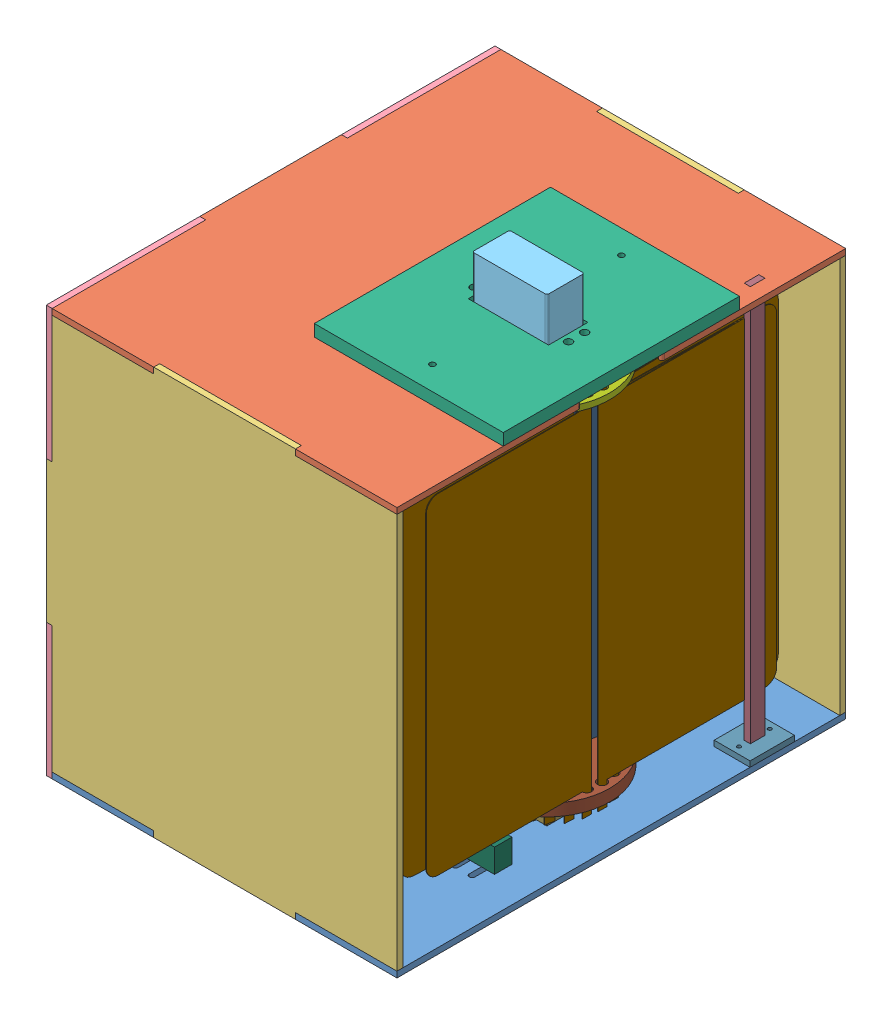
SolidWorks assembly BasicFlipbook, configuration Default. Lengths in mm.
Overall size (189.19 247.83 241.3).
43 component instances, 15 part files, 34 mates.
Components (placement in the parent):
- sidePanel-bearing-1: sidePanel-bearing [Default] at (77.8088 -538.0926 524.9276) size (188.59 3.17 241.3)
- sidePanel-spindle-1: sidePanel-spindle [Default] at (77.8088 -322.1926 524.9276) size (188.59 3.17 241.3)
- topPanel-1: topPanel [Default] at (170.5188 -428.5551 283.6276) x (0 -1 0) z (0 0 1) size (219.07 188.59 3.17)
- topPanel-2: topPanel [Default] at (170.5188 -428.5551 521.7526) x (0 -1 0) z (0 0 1) size (219.07 188.59 3.17)
- backPanel-1: backPanel [Default] at (77.8088 -538.0926 524.9276) x (0 1 0) z (0 0 1) size (219.07 3.17 241.3)
- servo-1: servo [Default] at (213.1908 -290.2676 404.2776) x (1 0 0) z (0 -1 0) size (52.83 20.07 43.1)
- sidePanel-motor-1: sidePanel-motor [Default] at (77.8088 -319.0176 524.9276) size (101.6 6.35 127)
- FlipHubAssy_11_14_16-2: FlipHubAssy_11_14_16 [Default] at (223.2238 -424.2676 404.2776) x (0 1 0) z (0.343761 0 0.939057) size (212.25 171.9 216.35) (flexible)
  - Hub_11_16_16v1-3: Hub_11_16_16v1 [Kerf Removed] at (92.075 0 0) x (0 -0.836215 0.548402) z (1 0 0) size (67.6 67.6 3.17)
  - 4mmShaft-1: 4mmShaft [Default] at (-110.65 0 0) x (0 0.397838 0.917456) z (1 0 0) size (4 4 201.85)
  - flipcard-2: flipcard [Default] at (101.6 -15.2897 -21.654) x (-1 0 0) z (0 0.118273 0.992981) size (203.2 0.36 88.9)
  - flipcard-3: flipcard [Default] at (101.6 -20.7049 -16.8264) x (-1 0 0) z (0 0.229727 0.973255) size (203.2 0.36 88.9)
  - flipcard-4: flipcard [Default] at (101.6 -24.7798 -10.679) x (-1 0 0) z (0 0.290896 0.956755) size (203.2 0.36 88.9)
  - flipcard-5: flipcard [Default] at (101.6 -27.1726 -3.6323) x (-1 0 0) z (0 0.324243 0.945974) size (203.2 0.36 88.9)
  - flipcard-6: flipcard [Default] at (101.6 -27.6554 3.8125) x (-1 0 0) z (0 0.355007 0.934864) size (203.2 0.36 88.9)
  - flipcard-7: flipcard [Default] at (101.6 6.9617 25.991) x (-1 0 0) z (0 -0.804275 -0.594258) size (203.2 0.36 88.9)
  - flipcard-8: flipcard [Default] at (101.6 13.6608 22.8217) x (-1 0 0) z (0 -0.829103 -0.559096) size (203.2 0.36 88.9)
  - flipcard-9: flipcard [Default] at (101.6 12.4258 -23.2935) x (-1 0 0) z (0 -0.27854 0.960425) size (203.2 0.36 88.9)
  - flipcard-10: flipcard [Default] at (101.6 19.1668 18.301) x (-1 0 0) z (0 -0.912348 -0.409415) size (203.2 0.36 88.9)
  - flipcard-11: flipcard [Default] at (101.6 25.8239 6.5692) x (-1 0 0) z (0 -0.973268 0.229671) size (203.2 0.36 88.9)
  - flipcard-12: flipcard [Default] at (101.6 -7.402 26.2839) x (-1 0 0) z (0 -0.588891 -0.808212) size (203.2 0.36 88.9)
  - flipcard-13: flipcard [Default] at (101.6 23.2571 13.1974) x (-1 0 0) z (0 -0.999195 0.040112) size (203.2 0.36 88.9)
  - flipcard-14: flipcard [Default] at (101.6 -0.029 26.9321) x (-1 0 0) z (0 -0.634806 -0.772672) size (203.2 0.36 88.9)
  - flipcard-15: flipcard [Default] at (101.6 -14.3329 23.6973) x (-1 0 0) z (0 -0.524162 -0.851618) size (203.2 0.36 88.9)
  - flipcard-16: flipcard [Default] at (101.6 25.5857 -7.2828) x (-1 0 0) z (0 -0.75236 0.658752) size (203.2 0.36 88.9)
  - flipcard-17: flipcard [Default] at (101.6 -20.2143 19.2851) x (-1 0 0) z (0 -0.387069 -0.922051) size (203.2 0.36 88.9)
  - flipcard-18: flipcard [Default] at (101.6 -26.2822 11.1902) x (-1 0 0) z (0 0.343761 0.939057) size (203.2 0.36 88.9)
  - flipcard-19: flipcard [Default] at (101.6 26.6468 -0.3343) x (-1 0 0) z (0 -0.879712 0.475507) size (203.2 0.36 88.9)
  - flipcard-20: flipcard [Default] at (101.6 -25.0081 13.5575) x (-1 0 0) z (0 -0.343761 -0.939057) size (203.2 0.36 88.9)
  - flipcard-21: flipcard [Default] at (101.6 22.7931 -13.6775) x (-1 0 0) z (0 -0.570443 0.821337) size (203.2 0.36 88.9)
  - flipcard-22: flipcard [Default] at (101.6 5.6236 -25.7226) x (-1 0 0) z (0 -0.165302 0.986243) size (203.2 0.36 88.9)
  - flipcard-23: flipcard [Default] at (101.6 -1.5593 -26.2681) x (-1 0 0) z (0 -0.043757 0.999042) size (203.2 0.36 88.9)
  - flipcard-24: flipcard [Default] at (101.6 18.5239 -19.098) x (-1 0 0) z (0 -0.319136 0.947709) size (203.2 0.36 88.9)
  - flipcard-26: flipcard [Default] at (101.6 -8.628 -24.8962) x (-1 0 0) z (0 0.08016 0.996782) size (203.2 0.36 88.9)
  - CenterSupport-2: CenterSupport [After Cut Kerf Removed] at (0 3.7916 3.0025) x (1 0 0) z (0 -0.836215 0.548402) size (190.5 19.05 3.05)
  - CenterSupport-3: CenterSupport [After Cut Kerf Removed] at (0 -3.0025 3.7916) x (1 0 0) z (0 -0.548402 -0.836215) size (190.5 19.05 3.05)
  - CenterSupport-4: CenterSupport [After Cut Kerf Removed] at (0 -3.7916 -3.0025) x (1 0 0) z (0 0.836215 -0.548402) size (190.5 19.05 3.05)
  - CenterSupport-5: CenterSupport [After Cut Kerf Removed] at (0 3.0025 -3.7916) x (1 0 0) z (0 0.548402 0.836215) size (190.5 19.05 3.05)
  - Hub_11_16_16v1-thicker-3: Hub_11_16_16v1-thicker [Kerf Removed] at (-95.25 0 0) x (0 -0.548402 -0.836215) z (1 0 0) size (67.6 72.68 6.35)
  - bearingSleeve-nut-1: bearingSleeve-nut [Default] at (-109.05 0 0) x (0 -0.939057 0.343761) z (-1 0 0) size (25.4 25.4 6.95)
- stopper-2: stopper [Default] at (255.3548 -538.0926 327.0616) x (0 1 0) z (-1 0 0) size (219.07 7.87 3.3)
- stopperSupport-1: stopperSupport [Default] at (243.9268 -531.9176 311.1876) x (1 0 0) z (0 -1 0) size (19.3 23.87 3)
- switchSupport-1: switchSupport [Default] at (224.5478 -534.9176 453.6616) x (1 0 0) z (0 1 0) size (19.84 9.4 12.7)
Mates (geometry in assembly coordinates):
- Coincident49: coincident anti-aligned: plane of servo-1 through (213.1908 -319.0176 404.2776) normal (0 1 0); plane of sidePanel-motor-1 through (77.8088 -319.0176 524.9276) normal (0 -1 0)
- Parallel2: parallel anti-aligned: plane of servo-1 through (193.1248 -328.3676 394.2446) normal (0 0 -1); plane of sidePanel-motor-1 through (191.4738 -319.0176 393.7048) normal (0 0 1)
- Coincident70: coincident anti-aligned: plane of sidePanel-spindle-1 through (77.8088 -319.0176 524.9276) normal (0 1 0); plane of sidePanel-motor-1 through (77.8088 -319.0176 524.9276) normal (0 -1 0)
- Coincident87: coincident aligned: plane of sidePanel-bearing-1 through (263.2288 -534.9176 524.9276) normal (1 0 0); plane of topPanel-1 through (263.2288 -322.1926 286.8026) normal (1 0 0)
- Coincident89: coincident aligned: plane of sidePanel-bearing-1 through (263.2288 -534.9176 524.9276) normal (1 0 0); plane of topPanel-1 through (263.2288 -322.1926 286.8026) normal (1 0 0)
- Coincident90: coincident anti-aligned: plane of sidePanel-bearing-1 through (77.8088 -534.9176 524.9276) normal (0 1 0); plane of topPanel-1 through (263.2288 -534.9176 286.8026) normal (0 -1 0)
- Coincident93: coincident anti-aligned: plane of sidePanel-bearing-1 through (77.8088 -534.9176 524.9276) normal (0 1 0); plane of topPanel-2 through (263.2288 -534.9176 524.9276) normal (0 -1 0)
- Coincident94: coincident aligned: plane of sidePanel-bearing-1 through (77.8088 -534.9176 524.9276) normal (0 0 1); plane of topPanel-2 through (170.5188 -428.5551 524.9276) normal (0 0 1)
- Coincident95: coincident aligned: plane of sidePanel-bearing-1 through (77.8088 -534.9176 524.9276) normal (-1 0 0); plane of topPanel-2 through (77.8088 -322.1926 524.9276) normal (-1 0 0)
- Coincident96: coincident anti-aligned: plane of sidePanel-spindle-1 through (77.8088 -322.1926 524.9276) normal (0 -1 0); plane of topPanel-1 through (263.2288 -322.1926 286.8026) normal (0 1 0)
- Coincident97: coincident aligned: plane of sidePanel-spindle-1 through (77.8088 -319.0176 283.6276) normal (0 0 -1); plane of topPanel-1 through (170.5188 -428.5551 283.6276) normal (0 0 -1)
- Coincident98: coincident aligned: plane of sidePanel-spindle-1 through (77.8088 -319.0176 524.9276) normal (-1 0 0); plane of topPanel-1 through (77.8088 -322.1926 286.8026) normal (-1 0 0)
- Coincident99: coincident anti-aligned: plane of topPanel-1 through (77.8088 -322.1926 286.8026) normal (-1 0 0); plane of backPanel-1 through (77.8088 -538.0926 524.9276) normal (1 0 0)
- Coincident100: coincident aligned: plane of sidePanel-bearing-1 through (77.8088 -538.0926 524.9276) normal (0 -1 0); plane of backPanel-1 through (74.6338 -538.0926 524.9276) normal (0 -1 0)
- Concentric23: concentric anti-aligned: cylinder of sidePanel-spindle-1 through (223.2238 -322.1926 404.2776) axis (0 1 0) radius 43.815; cylinder of FlipHubAssy_11_14_16-2/Hub_11_16_16v1-3 through (223.2238 -329.0176 404.2776) axis (0 -1 0) radius 33.8
- Concentric24: concentric anti-aligned: cylinder of sidePanel-bearing-1 through (231.1471 -538.0926 396.3543) axis (0 1 0) radius 1.0922; cylinder of FlipHubAssy_11_14_16-2/bearingSleeve-nut-1 through (231.1471 -527.9676 396.3543) axis (0 -1 0) radius 1.0922
- Concentric25: concentric anti-aligned: cylinder of sidePanel-bearing-1 through (215.3004 -538.0926 412.2009) axis (0 1 0) radius 1.0922; cylinder of FlipHubAssy_11_14_16-2/bearingSleeve-nut-1 through (215.3004 -527.9676 412.2009) axis (0 -1 0) radius 1.0922
- Parallel4: parallel aligned: line of sidePanel-bearing-1 through (263.2288 -534.9176 524.9276) axis (0 0 -1); line of FlipHubAssy_11_14_16-2/flipcard-18 through (252.1066 -513.1676 397.776) axis (0 0 -1)
- Parallel5: parallel anti-aligned: line of sidePanel-bearing-1 through (263.2288 -538.0926 524.9276) axis (0 0 -1); line of FlipHubAssy_11_14_16-2/flipcard-20 through (251.3683 -513.1676 416.387) axis (0 0 1)
- Coincident104: coincident aligned: plane of sidePanel-bearing-1 through (77.8088 -538.0926 524.9276) normal (0 -1 0); plane of stopper-2 through (252.0528 -538.0926 327.0616) normal (0 -1 0)
- Coincident105: coincident anti-aligned: plane of sidePanel-bearing-1 through (252.0528 -534.9176 327.0616) normal (0 0 -1); plane of stopper-2 through (252.0528 -538.0926 327.0616) normal (0 0 1)
- Coincident106: coincident anti-aligned: plane of sidePanel-bearing-1 through (255.3548 -534.9176 319.1876) normal (-1 0 0); plane of stopper-2 through (255.3548 -538.0926 327.0616) normal (1 0 0)
- Coincident107: coincident aligned: plane of sidePanel-bearing-1 through (263.2288 -534.9176 524.9276) normal (1 0 0); plane of stopperSupport-1 through (263.2288 -534.9176 335.0616) normal (1 0 0)
- Coincident108: coincident anti-aligned: plane of sidePanel-bearing-1 through (77.8088 -534.9176 524.9276) normal (0 1 0); plane of stopperSupport-1 through (243.9268 -534.9176 311.1876) normal (0 -1 0)
- Coincident109: coincident anti-aligned: plane of stopper-2 through (252.0528 -538.0926 319.1876) normal (0 0 -1); plane of stopperSupport-1 through (251.9268 -534.9176 319.1876) normal (0 0 1)
- Concentric30: concentric anti-aligned: cylinder of sidePanel-bearing-1 through (238.8238 -538.0926 450.4316) axis (0 1 0) radius 1.5; cylinder of switchSupport-1 through (238.8238 -522.2176 450.4316) axis (0 -1 0) radius 1.5
- Parallel6: parallel: line of topPanel-2 through (77.8088 -534.9176 521.7526) axis (1 0 0); plane of switchSupport-1 through (224.5478 -522.2176 453.6616) normal (0 0 1)
- Coincident110: coincident anti-aligned: plane of sidePanel-bearing-1 through (77.8088 -534.9176 524.9276) normal (0 1 0); plane of switchSupport-1 through (224.5478 -534.9176 453.6616) normal (0 -1 0)
- Concentric31: concentric aligned: circle of sidePanel-motor-1; circle of FlipHubAssy_11_14_16-2/Hub_11_16_16v1-3
- Parallel7: parallel aligned: plane of topPanel-1 through (170.5188 -428.5551 283.6276) normal (0 0 -1); plane of sidePanel-motor-1 through (263.2288 -312.6676 340.7776) normal (0 0 -1)
- Concentric32: concentric anti-aligned: cylinder of servo-1 through (223.2238 -333.3676 404.2776) axis (0 1 0) radius 3.5; cylinder of FlipHubAssy_11_14_16-2/4mmShaft-1 through (223.2238 -333.0676 404.2776) axis (0 -1 0) radius 2
- Distance2: distance = 10 mm anti-aligned: plane of FlipHubAssy_11_14_16-2/Hub_11_16_16v1-3 through (223.2238 -329.0176 404.2776) normal (0 1 0); plane of sidePanel-motor-1 through (77.8088 -319.0176 524.9276) normal (0 -1 0)
- Concentric33: concentric anti-aligned: cylinder of sidePanel-bearing-1 through (231.1471 -538.0926 396.3543) axis (0 1 0) radius 1.0922; cylinder of FlipHubAssy_11_14_16-2/bearingSleeve-nut-1 through (231.1471 -527.9676 396.3543) axis (0 -1 0) radius 1.0922
- Coincident111: coincident anti-aligned: plane of sidePanel-bearing-1 through (77.8088 -534.9176 524.9276) normal (0 1 0); plane of FlipHubAssy_11_14_16-2/bearingSleeve-nut-1 through (223.2238 -534.9176 404.2776) normal (0 -1 0)
